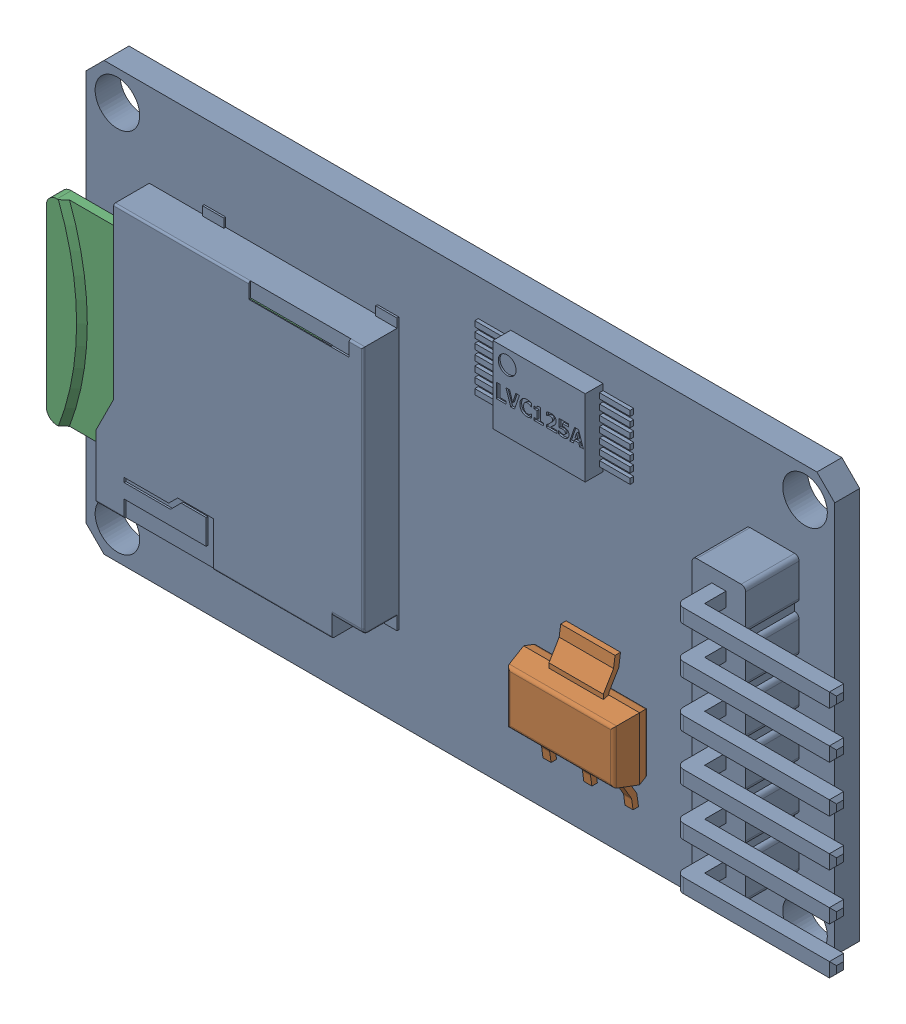
SolidWorks assembly MicroSD_Reader_Assembly, configuration Default. Lengths in mm.
Overall size (46.9 24 6.7).
4 component instances, 3 part files, 0 mates.
Components (placement in the parent):
- sdreader-1: sdreader [Default] at (-11.2744 2.632 -3.2) size (46.9 24 6.7)
  - Open CASCADE STEP translator 6.8 2.9.1.1.1-1: Open CASCADE STEP translator 6.8 2.9.1.1.1 [Default] at origin size (46.9 24 6.7)
- AMS1117-1: AMS1117 [Default] at (-0.4339 -2.128 -1.13) x (1 0 0) z (0 -1 0) size (6.51 1.86 7)
- card_sd-1: card_sd [Default] at (-21.187 5.4466 -0.36) x (0 -1 0) z (0 0 1) size (11 15 0.82)
